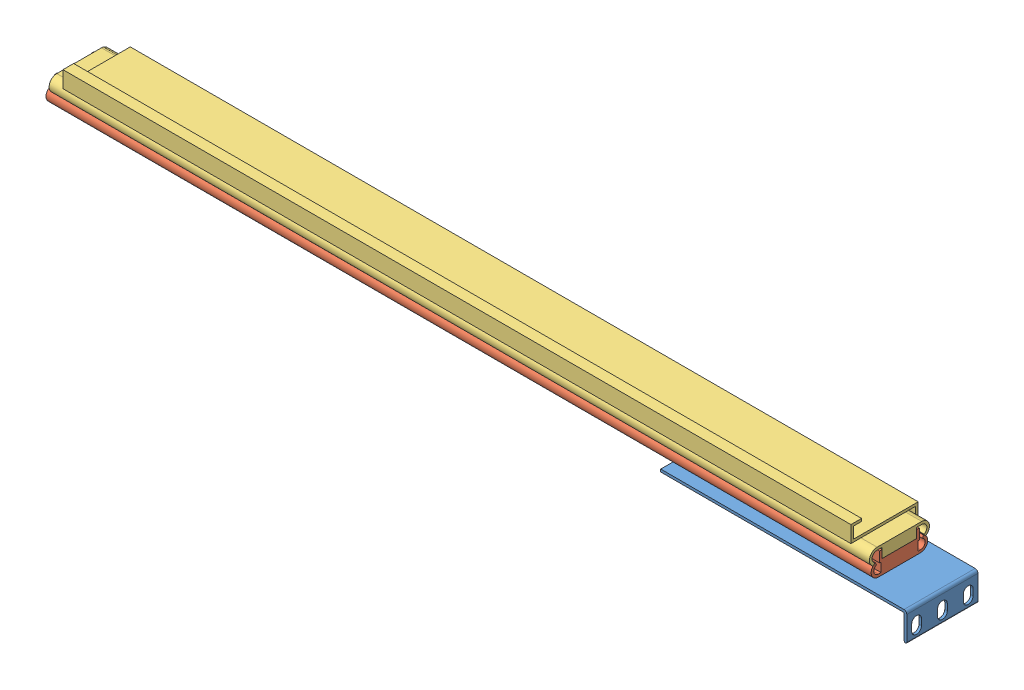
SolidWorks assembly Gleitschiene-Right, configuration Standard. Lengths in mm.
Overall size (537 44.1 44.05).
3 component instances, 3 part files, 7 mates.
Components (placement in the parent):
- winkel-1: winkel [Standard] at (51.9543 -6.5595 130.1) size (152.1 17.5 44)
- Schine-1: Schine [Standard] at (-484.2457 10.9405 134.15) x (0 1 0) z (1 0 0) size (13.6 35 510)
- Rolle-1: Rolle [Standard] at (15.7543 35.9405 170.05) x (0 1 0) z (-1 0 0) size (19.2 41.6 507)
Mates (geometry in assembly coordinates):
- Deckungsgleich1: coincident anti-aligned: plane of winkel-1 through (51.0043 10.9405 174.1) normal (0 1 0); plane of Schine-1 through (25.7543 10.9405 164.6513) normal (0 -1 0)
- Parallel1: parallel aligned: plane of winkel-1 through (52.7543 -5.7595 174.1) normal (1 0 0); plane of Schine-1 through (25.7543 15.4392 164.6513) normal (1 0 0)
- Abstand1: distance = 27 mm aligned: plane of winkel-1 through (52.7543 -5.7595 174.1) normal (1 0 0); plane of Schine-1 through (25.7543 15.4392 164.6513) normal (1 0 0)
- Abstand2: distance = 2 mm aligned: plane of Schine-1 through (25.7543 12.5405 163) normal (0 0 1); plane of winkel-1 through (8.7543 2.4905 165) normal (0 0 1)
- Deckungsgleich5: coincident anti-aligned: plane of Schine-1 through (25.7543 19.7405 141) normal (0 1 0); plane of Rolle-1 through (25.7543 19.7405 141) normal (0 -1 0)
- Deckungsgleich6: coincident anti-aligned: plane of Schine-1 through (25.7543 24.5405 141) normal (0 0 1); plane of Rolle-1 through (25.7543 25.7405 141) normal (0 0 -1)
- LimitAbstand2: limit distance = 0 mm aligned: plane of Schine-1 through (25.7543 15.4392 164.6513) normal (1 0 0); plane of Rolle-1 through (25.7543 22.5716 137.85) normal (1 0 0)
